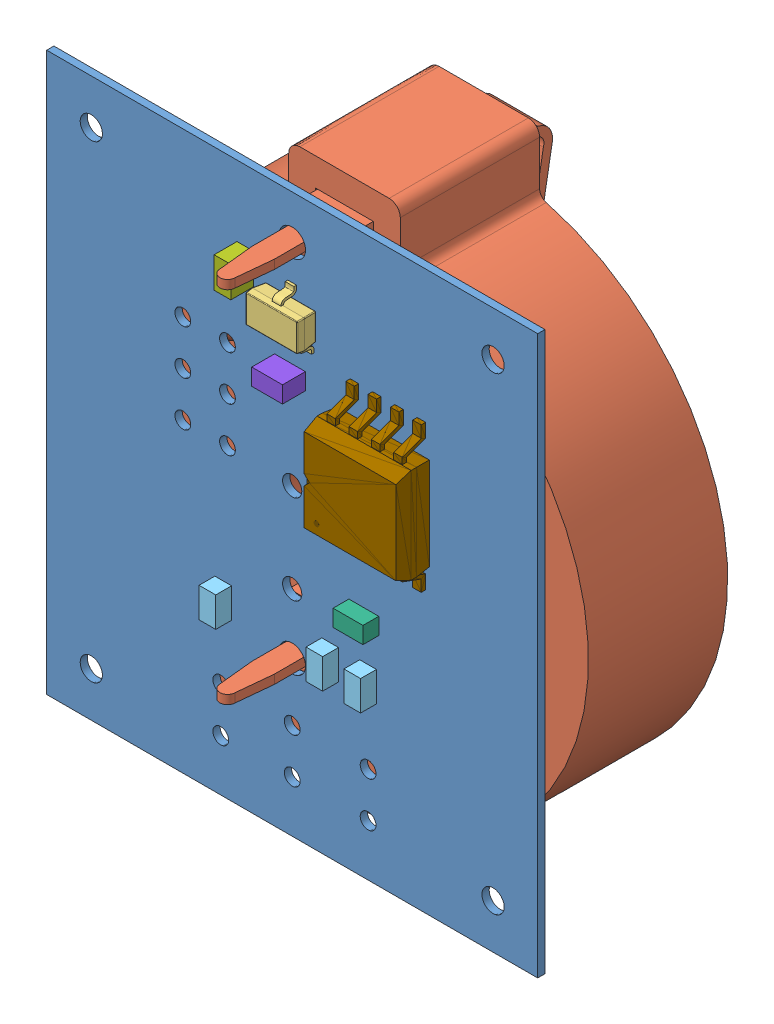
SolidWorks assembly Final Flashlight PCB, configuration Default. Lengths in mm.
Overall size (27.94 31.75 17.34).
27 component instances, 9 part files, 0 mates.
Components (placement in the parent):
- Board_1-1: Board_1 [Default] at origin size (27.94 31.75 0.41)
- Imported_1-1: Imported_1 [Default] at origin size (27.76 30.96 17.34)
  - keystone-PN1025-7_1-1: keystone-PN1025-7_1 [Default] at (13.9955 14.1608 -2.9515) x (1 0 0) z (0 1 0) size (27.76 17.34 30.96)
- U1_1-1: U1_1 [Default] at origin size (3.01 2.91 1.23)
  - SOT23-3_1-1: SOT23-3_1 [Default] at (13.9939 25.8873 0) x (0 -1 0) z (0 0 1) size (2.91 3.01 1.23)
  - 5808185472-1: 5808185472 [Default] at (14.097 26.162 0) size (0.25 0.25 0.25)
    - Extruded_1-1: Extruded_1 [Default] at origin size (0.25 0.25 0.25)
- R3_1-1: R3_1 [Default] at origin size (0.95 1.7 0.9)
  - 5808185088-1: 5808185088 [Default] at (18.288 9.767 0) size (0.95 1.7 0.9)
    - Extruded_1_2-1: Extruded_1_2 [Default] at origin size (0.95 1.7 0.9)
- R2_1-1: R2_1 [Default] at origin size (0.95 1.7 0.9)
  - 5808185088-1: 5808185088 [Default] at (16.129 9.767 0) size (0.95 1.7 0.9)
    - Extruded_1_2-1: Extruded_1_2 [Default] at origin size (0.95 1.7 0.9)
- R1_1-1: R1_1 [Default] at origin size (0.95 1.7 0.9)
  - 5808185088-1: 5808185088 [Default] at (10.045 9.767 0) size (0.95 1.7 0.9)
    - Extruded_1_2-1: Extruded_1_2 [Default] at origin size (0.95 1.7 0.9)
- R4_1-1: R4_1 [Default] at origin size (1.7 0.95 0.9)
  - 5808184896-1: 5808184896 [Default] at (18.046 12.827 0) size (1.7 0.95 0.9)
    - Extruded_1_3-1: Extruded_1_3 [Default] at origin size (1.7 0.95 0.9)
- C2_1-1: C2_1 [Default] at origin size (0.95 1.75 1.3)
  - 5808185280-1: 5808185280 [Default] at (11.303 26.859 0) size (0.95 1.75 1.3)
    - Extruded_1_4-1: Extruded_1_4 [Default] at origin size (0.95 1.75 1.3)
- C1_1-1: C1_1 [Default] at origin size (1.75 0.95 1.3)
  - 5808184704-1: 5808184704 [Default] at (13.843 22.795 0) size (1.75 0.95 1.3)
    - Extruded_1_5-1: Extruded_1_5 [Default] at origin size (1.75 0.95 1.3)
- ATTiny85_1-1: ATTiny85_1 [Default] at origin size (5.36 8.25 2.16)
  - 8S2_1-1: 8S2_1 [Default] at (19.4181 20.066 0) x (0 1 0) z (0 0 1) size (8.25 5.36 2.16)
